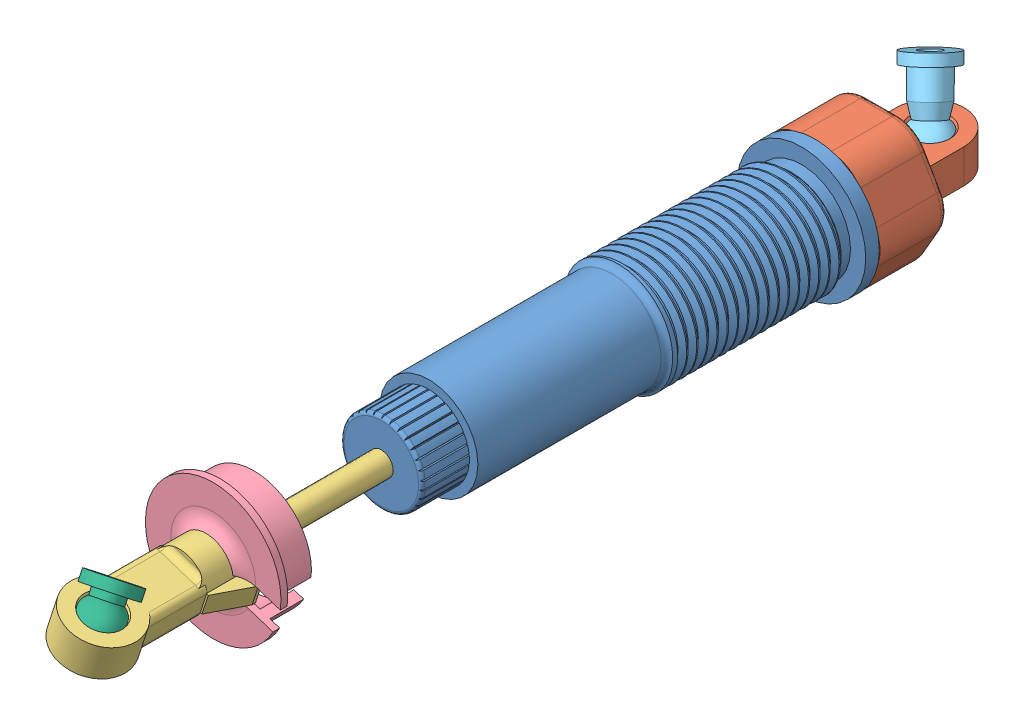
SolidWorks assembly Spring, configuration Default. Lengths in mm.
Overall size (25.05 25.15 136.67).
6 component instances, 6 part files, 10 mates.
Components (placement in the parent):
- Spring_1-1: Spring_1 [Default] at origin size (19 19 64)
- Spring_2-1: Spring_2 [Default] at (0 0 -64) x (1 0 0) z (0 1 0) size (19.24 21.99 18)
- Spring_3-1: Spring_3 [Default] at (0 0 28.8193) x (-0.308657 -0.951173 0) z (0 0 1) size (8 11.01 88)
- Spring_4-1: Spring_4 [Default] at (0 0 28.8193) x (-0.308657 -0.951173 0) z (0 0 1) size (20 19.85 10)
- Ball_1-1: Ball_1 [Default] at (1.1839 -2.922 -79.8032) x (0.73404 0.019363 -0.67883) z (0.351061 -0.866489 0.354898) size (7 7 13.5)
- Ball_2-1: Ball_2 [Default] at (0.5492 -2.8329 44.0094) x (0.976498 0.028415 -0.213643) z (0.154838 -0.782025 0.603707) size (7 7 9)
Mates (geometry in assembly coordinates):
- Concentric1: concentric aligned: cylinder of Spring_1-1 through (0 0 0) axis (0 0 1) radius 1.75; cylinder of Spring_3-1 through (0 0 28.8193) axis (0 0 1) radius 1.75
- LimitDistance1: limit distance = 23.8193 mm anti-aligned: plane of Spring_3-1 through (0 0 23.8193) normal (0 0 -1); plane of Spring_1-1 through (0 1.75 0) normal (0 0 1)
- Concentric2: concentric aligned: cylinder of Spring_3-1 through (0 0 28.8193) axis (0 0 1) radius 1.75; cylinder of Spring_4-1 through (0 0 28.8193) axis (0 0 1) radius 7
- Parallel1: parallel aligned: plane of Spring_3-1 through (-0.463 -1.4268 29.8193) normal (-0.308657 -0.951173 0); plane of Spring_4-1 through (0.5402 1.6646 28.8193) normal (-0.308657 -0.951173 0)
- Coincident4: coincident aligned: plane of Spring_3-1 through (0 0 23.8193) normal (0 0 -1); plane of Spring_4-1 through (6.6582 -2.1606 23.8193) normal (0 0 -1)
- Coincident6: coincident anti-aligned: plane of Spring_1-1 through (0 9.5 -64) normal (0 0 -1); plane of Spring_2-1 through (0 0 -64) normal (0 0 1)
- Concentric7: concentric aligned: cylinder of Spring_1-1 through (0 0 0) axis (0 0 1) radius 9.5; cylinder of Spring_2-1 through (0 0 -75) axis (0 0 1) radius 6
- Parallel2: parallel anti-aligned: plane of Spring_2-1 through (0 -2.5 -69) normal (0 -1 0); plane of assembly through (0 0 0) normal (0 1 0)
- Concentric8: concentric: sphere of Spring_2-1; sphere of Ball_1-1
- Concentric9: concentric: sphere of Spring_3-1; sphere of Ball_2-1
